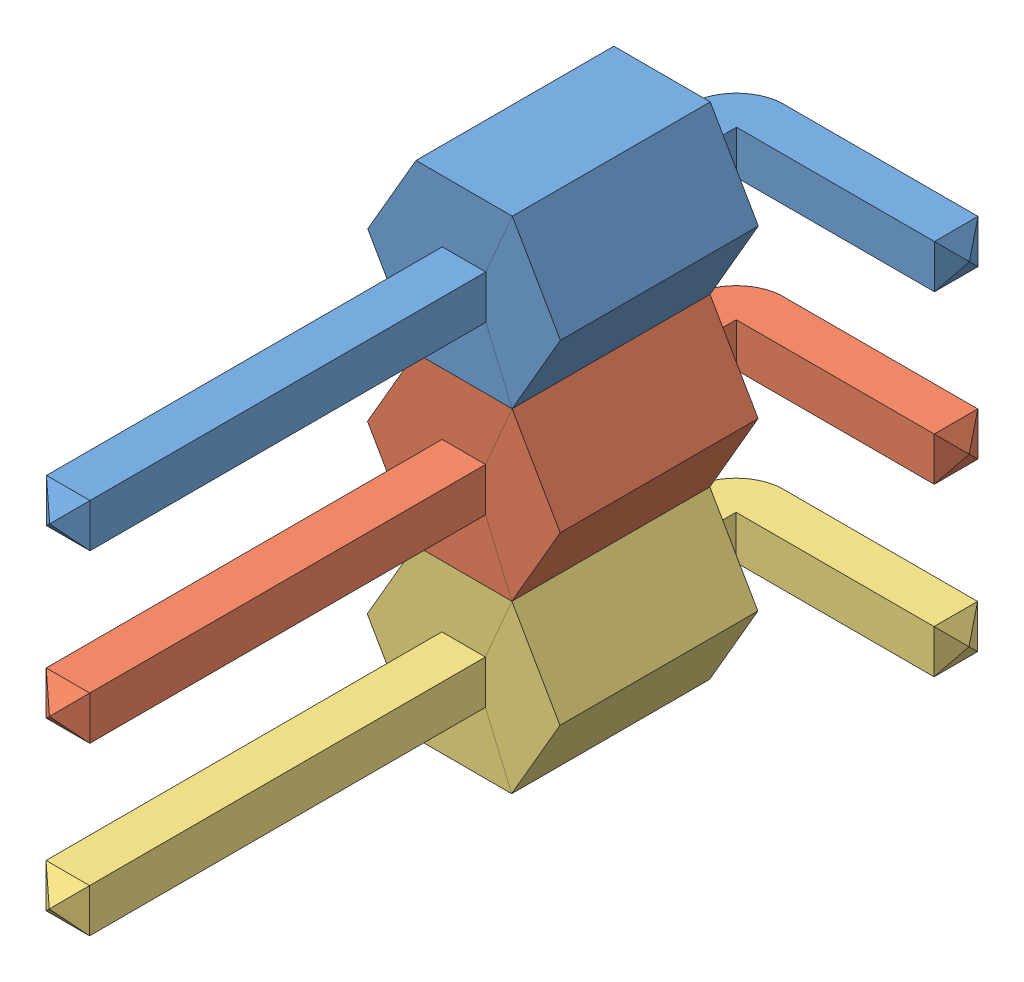
SolidWorks assembly PIN_HEADER_L-ANGLE, configuration Default. Lengths in mm.
Overall size (4.98 7.95 10.7).
3 component instances, 3 part files, 0 mates.
Components (placement in the parent):
- Group_28-1: Group_28 [Default] at (0.0033 2.5199 0) size (4.97 2.91 10.7)
- Group_25-1: Group_25 [Default] at origin size (4.97 2.91 10.7)
- Group_29-1: Group_29 [Default] at (-0.0033 -2.5199 0) size (4.97 2.91 10.7)
